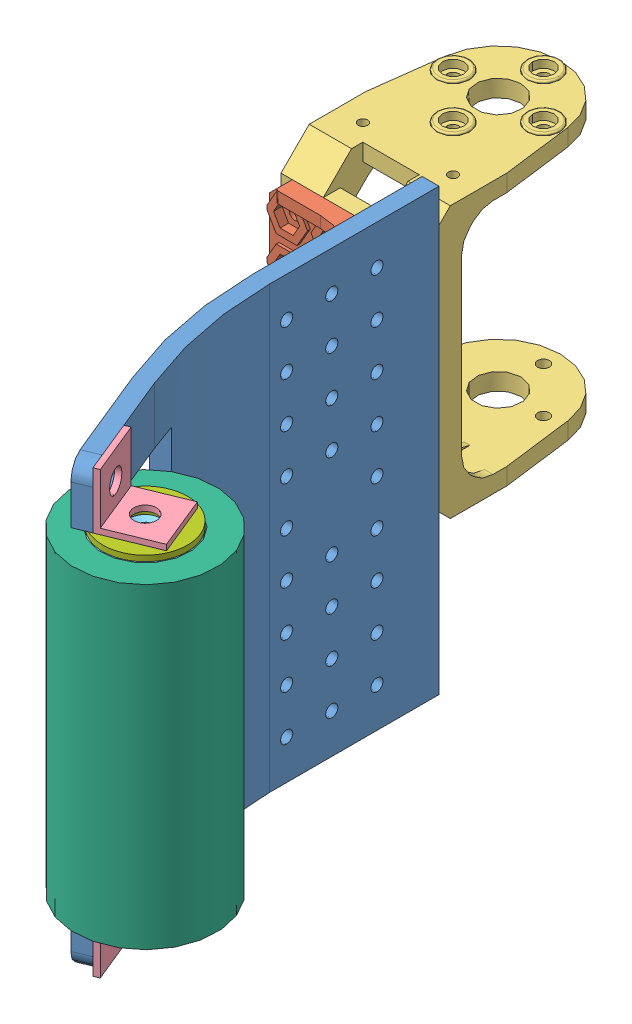
SolidWorks assembly essai_assemblage_pince_3_gauche, configuration Default. Lengths in mm.
Overall size (56.85 78 117.91).
10 component instances, 7 part files, 22 mates.
Components (placement in the parent):
- essai_pince_6-1: essai_pince_6 [Default] at (-8.4781 -11.6289 -22.4125) size (15.55 78 75)
- F9ORG-1: F9ORG [Défaut] at (-8.4781 27.3871 -52.4125) x (1 0 0) z (0 0 -1) size (24 24 30)
- F2-1: F2 [Défaut] at (-20.9781 35.3711 -78.4125) x (0 1 0) z (0 0 1) size (48.81 25 37)
- corniere_10x10-3: corniere_10x10 [Default] at (12.5438 56.3711 8.412) x (-0.925648 0 0.378386) z (-0.378386 0 -0.925648) size (10 10 10)
- corniere_10x10-2: corniere_10x10 [Default] at (16.3277 -1.6289 17.6684) x (-0.925648 0 0.378386) z (0.378386 0 0.925648) size (10 10 10)
- F9ORG-2: F9ORG [Défaut] at (-8.4781 43.3711 -52.4125) x (1 0 0) z (0 0 -1) size (24 24 30)
- Rouleau_Laiton_D15_H56-1: Rouleau_Laiton_D15_H56 [Défaut] at (9.8075 -0.6289 14.9321) size (15 56 15)
- Rouleau_D25_H56-1: Rouleau_D25_H56 [Default] at (9.8075 -0.6289 14.9321) x (0.08937 0 0.995998) z (-0.995998 0 0.08937) size (25 56 25)
- Rondelle_M5_Large-1: Rondelle_M5_Large [Défaut] at (9.8075 55.3711 14.9321) x (-0.555891 0 0.831255) z (-0.831255 0 -0.555891) size (15 1 15)
- Rondelle_M5_Large-2: Rondelle_M5_Large [Défaut] at (9.8075 -1.6289 14.9321) x (-0.793326 0 -0.608798) z (0.608798 0 -0.793326) size (15 1 15)
Mates (geometry in assembly coordinates):
- Coïncidente3: coincident anti-aligned: plane of ? through (-33.4781 39.3871 -51.9793) normal (0 -0.03675 -0.999324); plane of ? through (-33.4781 10.9939 -50.9351) normal (0 0.03675 0.999324)
- Coïncidente4: coincident aligned: plane of ? through (-8.4781 39.3871 -51.9793) normal (1 0 0); plane of ? through (-8.4781 10.9939 -50.9351) normal (1 0 0)
- Coïncidente5: coincident anti-aligned: plane of corniere_10x10-3 through (3.2873 57.3711 12.1958) normal (-0.925648 0 0.378386); plane of essai_pince_6-1 through (-0.4965 66.3711 2.9393) normal (0.925648 0 -0.378386)
- Coïncidente7: coincident anti-aligned: plane of essai_pince_6-1 through (-0.4965 66.3711 2.9393) normal (0.925648 0 -0.378386); plane of corniere_10x10-2 through (7.0712 -2.6289 21.4523) normal (-0.925648 0 0.378386)
- Coïncidente15: coincident anti-aligned: plane of essai_pince_6-1 through (-8.4781 66.3711 -22.4125) normal (-1 0 0); plane of ? through (-8.4781 39.3871 -51.9793) normal (1 0 0)
- Coïncidente16: coincident anti-aligned: plane of ? through (-33.4781 10.9939 -50.9351) normal (0 0.03675 0.999324); plane of ? through (-33.4781 54.9642 -52.5521) normal (0 -0.03675 -0.999324)
- Coïncidente17: coincident anti-aligned: plane of essai_pince_6-1 through (-8.4781 66.3711 -22.4125) normal (-1 0 0); plane of ? through (-8.4781 54.9642 -52.5521) normal (1 0 0)
- Coaxiale13: concentric aligned: cylinder of essai_pince_6-1; cylinder of corniere_10x10-3
- Parallèle1: parallel aligned: plane of essai_pince_6-1 through (32.9437 56.3711 10.8761) normal (0 -1 0); plane of corniere_10x10-3 through (16.3277 56.3711 17.6684) normal (0 -1 0)
- Coaxiale14: concentric aligned: cylinder of Rouleau_Laiton_D15_H56-1; cylinder of Rouleau_D25_H56-1
- Coïncidente19: coincident aligned: plane of Rouleau_Laiton_D15_H56-1 through (9.8075 55.3711 14.9321) normal (0 1 0); plane of Rouleau_D25_H56-1 through (9.8075 55.3711 14.9321) normal (0 1 0)
- Coaxiale15: concentric aligned: cylinder of essai_pince_6-1; cylinder of corniere_10x10-2
- Coïncidente20: coincident aligned: plane of essai_pince_6-1 through (32.9437 -1.6289 10.8761) normal (0 1 0); plane of corniere_10x10-2 through (12.5438 -1.6289 8.412) normal (0 1 0)
- Coaxiale16: concentric aligned: cylinder of corniere_10x10-3; cylinder of Rouleau_Laiton_D15_H56-1
- Coaxiale17: concentric aligned: cylinder of Rouleau_Laiton_D15_H56-1; cylinder of Rondelle_M5_Large-2
- Coaxiale18: concentric aligned: cylinder of Rouleau_Laiton_D15_H56-1; cylinder of Rondelle_M5_Large-1
- Coïncidente21: coincident aligned: plane of Rouleau_Laiton_D15_H56-1 through (9.8075 55.3711 14.9321) normal (0 1 0); circle of Rondelle_M5_Large-1
- Coïncidente22: coincident anti-aligned: plane of Rouleau_Laiton_D15_H56-1 through (9.8075 -0.6289 14.9321) normal (0 -1 0); plane of Rondelle_M5_Large-2 through (9.8075 -0.6289 14.9321) normal (0 1 0)
- Coïncidente23: coincident anti-aligned: plane of corniere_10x10-2 through (12.5438 -1.6289 8.412) normal (0 1 0); plane of Rondelle_M5_Large-2 through (9.8075 -1.6289 14.9321) normal (0 -1 0)
- Coaxiale21: concentric anti-aligned: cylinder of ?; cylinder of ?
- Coaxiale22: concentric aligned: cylinder of essai_pince_6-1; cylinder of ?
- Coaxiale23: concentric aligned: cylinder of essai_pince_6-1; cylinder of ?
